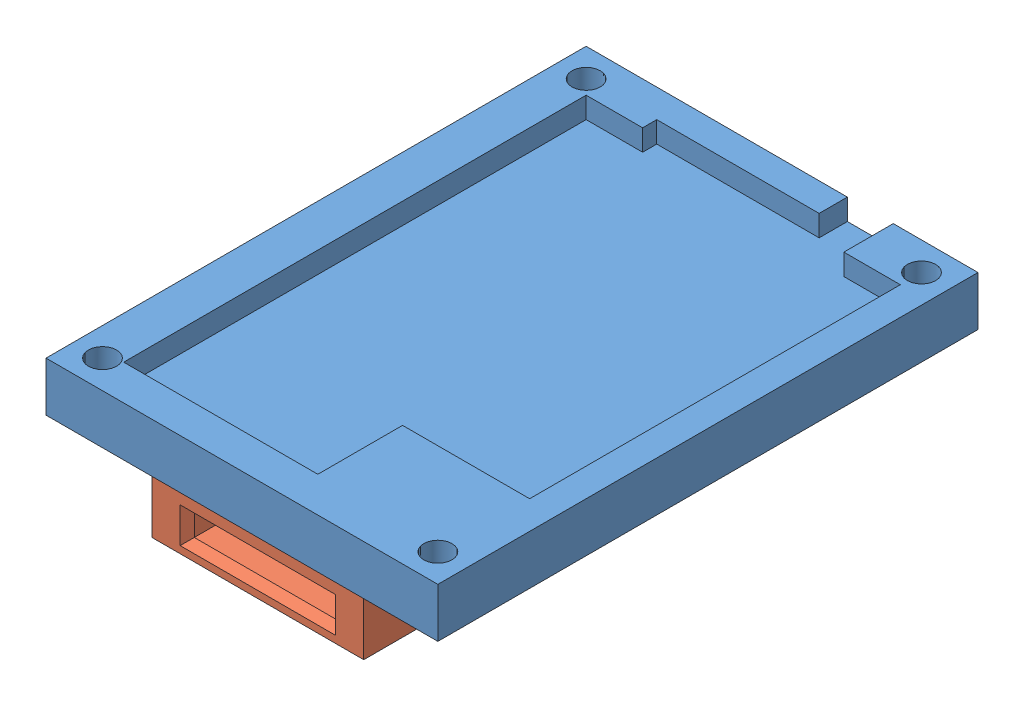
SolidWorks assembly nosilec_reley, configuration Default. Lengths in mm.
Overall size (55.5 17 76.5).
2 component instances, 2 part files, 3 mates.
Components (placement in the parent):
- podstavek_reley-1: podstavek_reley [Default] at (30.8144 45.535 53.7148) size (55.5 7 76.5)
- din_nosilec-1: din_nosilec [Default] at (45.8877 45.535 73.2425) x (0 0 -1) z (-1 0 0) size (70 10 30)
Mates (geometry in assembly coordinates):
- Coincident1: coincident: plane of podstavek_reley-1 through (30.8144 45.535 53.7148) normal (0 -1 0); plane of din_nosilec-1 through (45.8877 45.535 73.2425) normal (0 1 0)
- Distance1: distance = 2.5 mm: plane of din_nosilec-1 through (51.8248 41.535 101.4454) normal (0 0 1); plane of podstavek_reley-1 through (9.3248 49.535 103.9454) normal (0 0 1)
- Distance2: distance = 12.5 mm aligned: plane of din_nosilec-1 through (21.8248 41.535 101.4454) normal (-1 0 0); plane of podstavek_reley-1 through (9.3248 49.535 27.4454) normal (-1 0 0)
